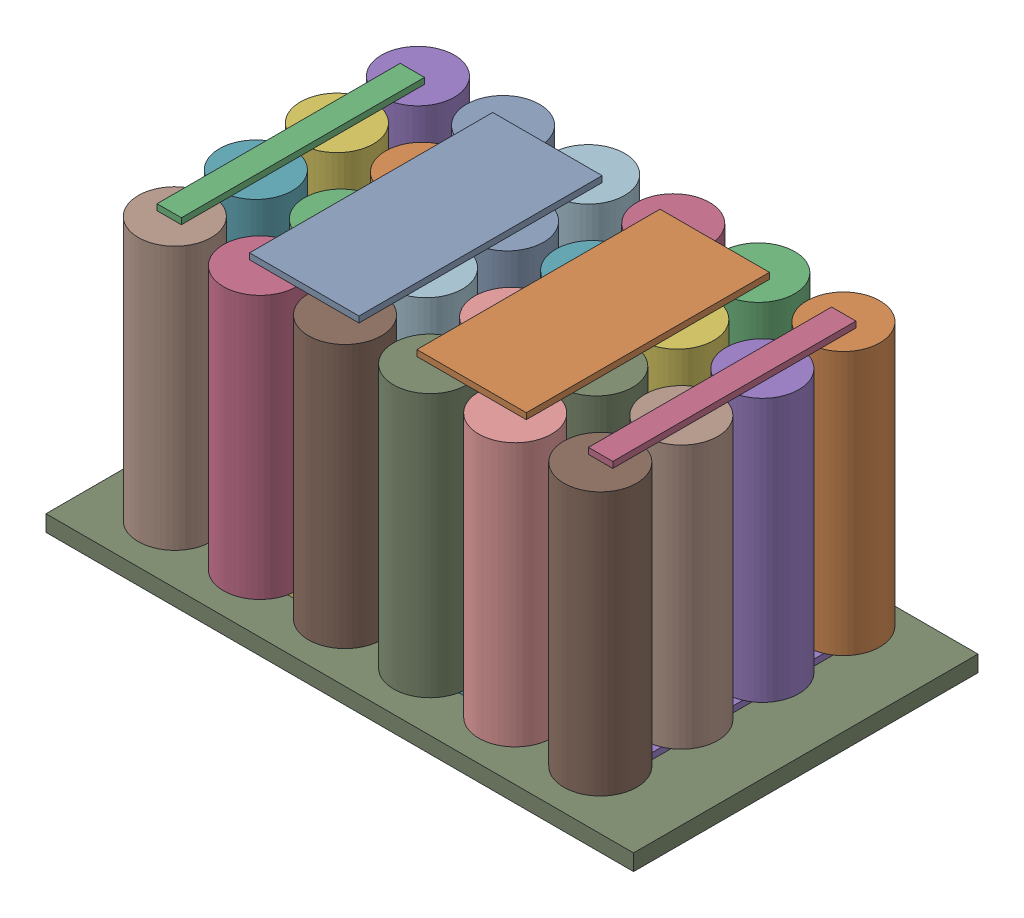
SolidWorks assembly 6s4p battery module, configuration Default. Lengths in mm.
Overall size (145 72 85).
10 component instances, 4 part files, 12 mates.
Components (placement in the parent):
- 6s4p-1: 6s4p [Default] at (656.2051 831.7288 1273.6569) size (123 65 78)
- bush2-1: bush2 [Default] at (635.6998 896.7288 1273.6969) size (27 1.5 60)
- bush2-2: bush2 [Default] at (677.015 896.7288 1273.7232) size (27 1.5 60)
- bushbar-1: bushbar [Default] at (603.2834 896.7288 1274.6194) size (6 1.5 60)
- bushbar-2: bushbar [Default] at (708.5923 896.7288 1273.4631) size (6 1.5 60)
- bushbar-5: bushbar [Default] at (709.1801 830.2288 1273.841) size (6 1.5 60)
- bush2-4: bush2 [Default] at (634.8147 830.2288 1274.0716) size (27 1.5 60)
- bush2-5: bush2 [Default] at (677.3423 830.2288 1273.8979) x (0.999984 0 -0.005722) z (0.005722 0 0.999984) size (27 1.5 60)
- bushbar-7: bushbar [Default] at (605.4809 830.2288 1275.1397) size (6 1.5 60)
- Al cooling plate-4: Al cooling plate [Default] at (657.3305 826.2288 1274.0716) size (145 4 85)
Mates (geometry in assembly coordinates):
- Coincident1: coincident anti-aligned: plane of 6s4p-1 through (624.7051 896.7288 1243.6569) normal (0 1 0); plane of bush2-1 through (635.6998 896.7288 1273.6969) normal (0 -1 0)
- Coincident8: coincident anti-aligned: plane of 6s4p-1 through (708.7051 896.7288 1243.6569) normal (0 1 0); plane of bushbar-2 through (708.5923 896.7288 1273.4631) normal (0 -1 0)
- Coincident9: coincident: plane of 6s4p-1 through (603.7051 896.7288 1243.6569) normal (0 1 0); plane of bushbar-1 through (603.2834 896.7288 1274.6194) normal (0 -1 0)
- Coincident16: coincident: plane of 6s4p-1 through (603.7051 831.7288 1303.6569) normal (0 -1 0); plane of bushbar-5 through (709.1801 831.7288 1273.841) normal (0 1 0)
- Coincident18: coincident anti-aligned: plane of 6s4p-1 through (624.7051 831.7288 1303.6569) normal (0 -1 0); plane of bush2-4 through (634.8147 831.7288 1274.0716) normal (0 1 0)
- Coincident19: coincident anti-aligned: plane of 6s4p-1 through (666.7051 831.7288 1303.6569) normal (0 -1 0); plane of bush2-5 through (677.3423 831.7288 1273.8979) normal (0 1 0)
- Coincident20: coincident: plane of 6s4p-1 through (708.7051 831.7288 1303.6569) normal (0 -1 0); plane of bushbar-5 through (709.1801 831.7288 1273.841) normal (0 1 0)
- Coincident21: coincident: plane of 6s4p-1 through (603.7051 831.7288 1303.6569) normal (0 -1 0); plane of bushbar-7 through (605.4809 831.7288 1275.1397) normal (0 1 0)
- Coincident22: coincident anti-aligned: plane of 6s4p-1 through (666.7051 896.7288 1303.6569) normal (0 1 0); plane of bush2-2 through (677.015 896.7288 1273.7232) normal (0 -1 0)
- Coincident27: coincident anti-aligned: plane of bush2-5 through (677.3423 830.2288 1273.8979) normal (0 -1 0); plane of Al cooling plate-4 through (657.3305 830.2288 1274.0716) normal (0 1 0)
- Width7: width aligned: plane of bushbar-7 through (602.4809 831.7288 1305.1397) normal (-1 0 0); plane of Al cooling plate-4 through (712.1801 831.7288 1303.841) normal (1 0 0); plane of bushbar-5 through (584.8305 830.2288 1316.5716) normal (-1 0 0); plane of Al cooling plate-4 through (729.8305 830.2288 1316.5716) normal (1 0 0)
- Width8: width anti-aligned: plane of bush2-4 through (648.3147 831.7288 1304.0716) normal (0 0 1); plane of Al cooling plate-4 through (648.3147 831.7288 1244.0716) normal (0 0 -1); plane of bush2-4 through (584.8305 830.2288 1231.5716) normal (0 0 -1); plane of Al cooling plate-4 through (584.8305 830.2288 1316.5716) normal (0 0 1)
